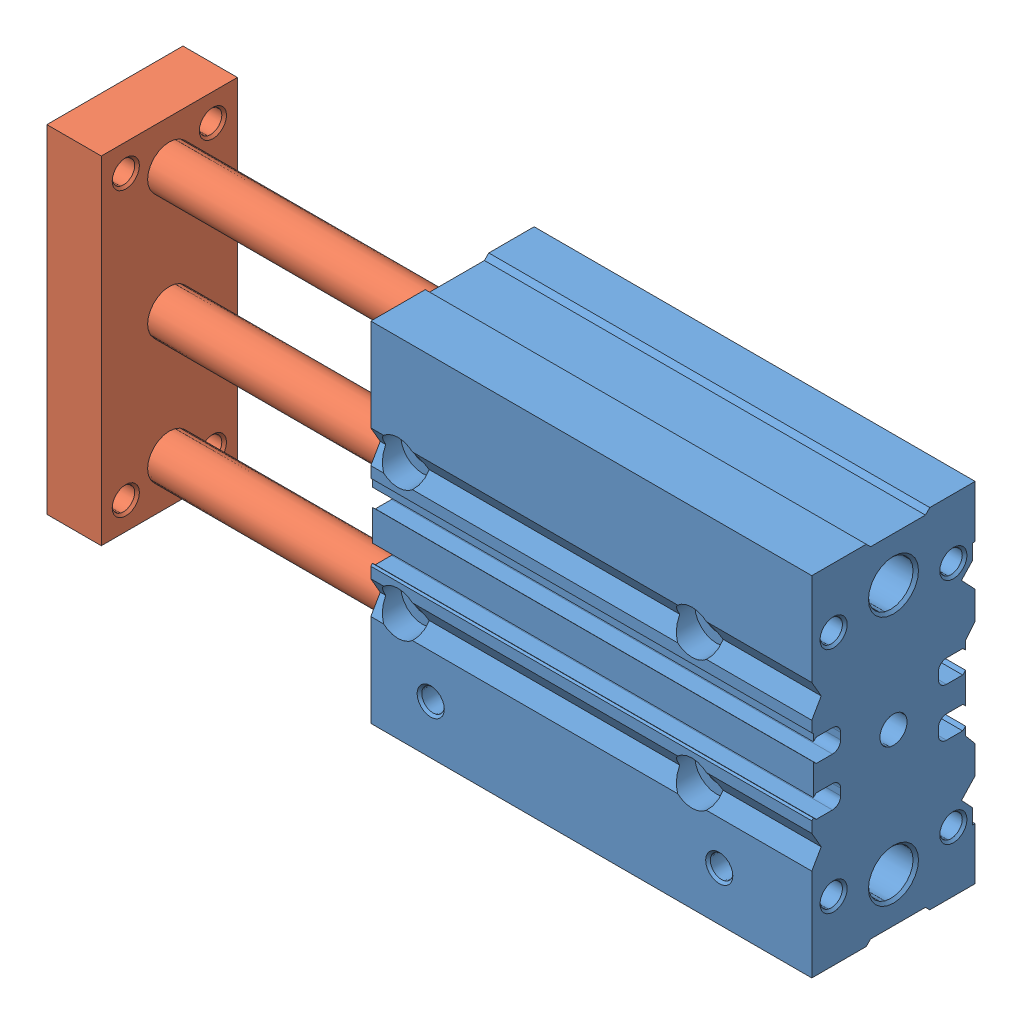
SolidWorks assembly 0059_003_MGCLB16-50, configuration Default. Lengths in mm.
Overall size (143 64 30).
2 component instances, 2 part files, 3 mates.
Components (placement in the parent):
- 0059_Z_MGCLB16_50b-2: 0059_Z_MGCLB16_50b [Default] at origin size (81 64 30)
- 0059_Z_MGCLB16_50s-1: 0059_Z_MGCLB16_50s [Default] at (-62 0 0) size (114 62 25)
Mates (geometry in assembly coordinates):
- Concentric1: concentric: cylinder of 0059_Z_MGCLB16_50b-2 through (81 23 0) axis (-1 0 0) radius 4.1; cylinder of 0059_Z_MGCLB16_50s-1 through (52 23 0) axis (-1 0 0) radius 4
- Concentric2: concentric: cylinder of 0059_Z_MGCLB16_50b-2 through (81 -23 0) axis (-1 0 0) radius 4.1; cylinder of 0059_Z_MGCLB16_50s-1 through (52 -23 0) axis (-1 0 0) radius 4
- LimitDistance1: limit distance = 52 mm: plane of 0059_Z_MGCLB16_50s-1 through (-52 -31 12.5) normal (1 0 0); plane of 0059_Z_MGCLB16_50b-2 through (0 -4.4444 -11.221) normal (-1 0 0)
